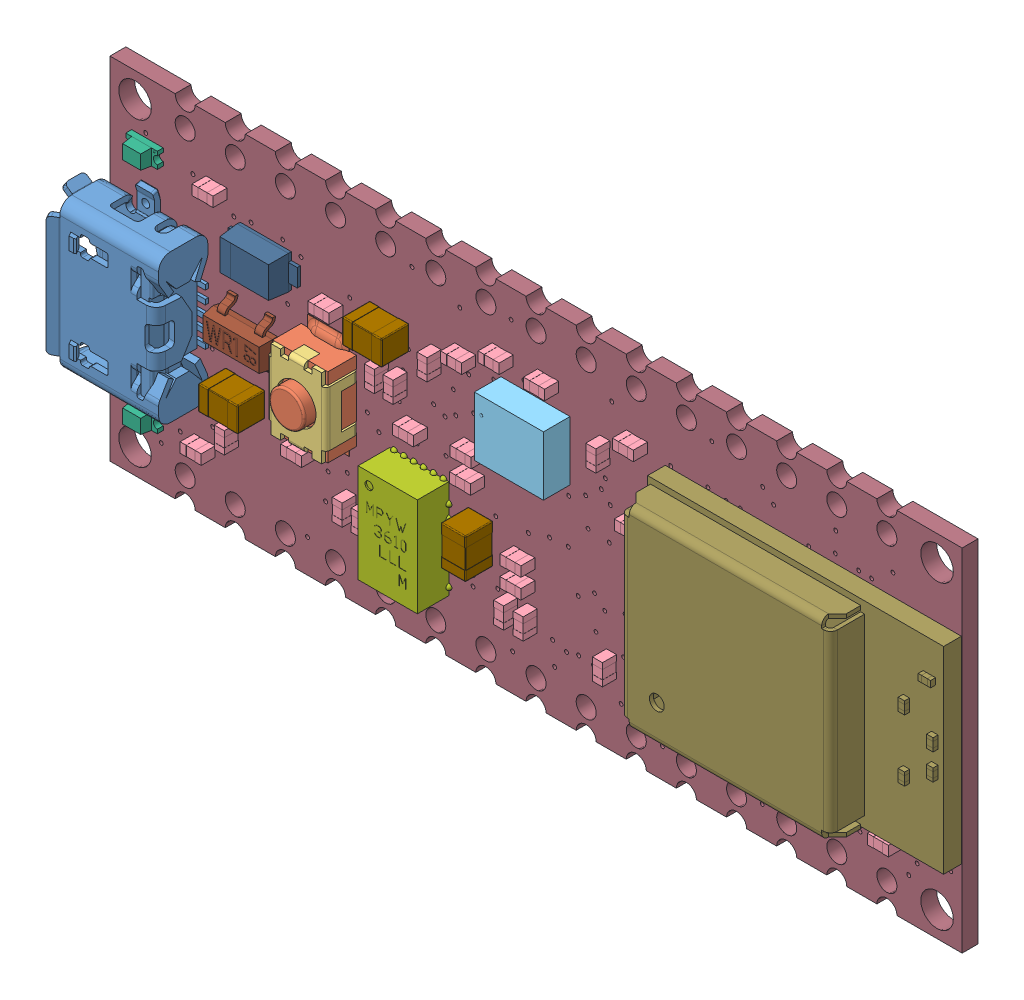
SolidWorks assembly Nano33BLE.step, configuration Default. Lengths in mm.
Overall size (43.8 17.78 3.58).
48 component instances, 13 part files, 0 mates.
Components (placement in the parent):
- NANO33BLE_V2.0 v1.step-1: NANO33BLE_V2.0 v1.step [Default] at origin size (43.8 17.78 3.58)
  - 3DComponents.step-1: 3DComponents.step [Default] at origin size (43.76 12.41 2.95)
    - zx62-ab-5pa_31_ v1.step-1: zx62-ab-5pa_31_ v1.step [Default] x (-1 0 0) z (0 1 0) size (5.6 2.95 8.8)
      - 6850961.step-1: 6850961.step [Default] at origin size (5.6 2.95 8.8)
        - ZX62-AB-5PA (1).step-1: ZX62-AB-5PA (1).step [Default] at (-4.98 1.125 5.465) size (5.6 2.95 8.8)
    - IoT_Reser Button v1.step-1: IoT_Reser Button v1.step [Default] x (0 -1 0) z (-1 0 0) size (5.2 2.15 3)
      - User Library-arduino_nano_reset core.step-1: User Library-arduino_nano_reset core.step [Default] at (-8.89 0.805 -11.09) size (5.2 2.15 2.8)
      - User Library-arduino_nano_reset shell.step-1: User Library-arduino_nano_reset shell.step [Default] at (-8.89 2.455 -11.09) x (0 0 1) z (-1 0 0) size (3 1.65 4)
    - RC0402FR-071KL.step-1: RC0402FR-071KL.step [Default] at origin size (35.89 12.12 0.71)
      - RC0402FR-071KL RC0402N_YAG v1.step-1: RC0402FR-071KL RC0402N_YAG v1.step [Default] at (4.8 3.0875 0.805) size (1.07 0.51 0.71)
      - RC0402FR-071KL RC0402N_YAG v1.step-2: RC0402FR-071KL RC0402N_YAG v1.step [Default] at (6.25 4.4075 0.805) x (0 -1 0) z (0 0 1) size (1.07 0.51 0.71)
      - RC0402FR-071KL RC0402N_YAG v1.step-3: RC0402FR-071KL RC0402N_YAG v1.step [Default] at (9.8875 5.5375 0.805) size (1.07 0.51 0.71)
      - RC0402FR-071KL RC0402N_YAG v1.step-4: RC0402FR-071KL RC0402N_YAG v1.step [Default] at (11.27 12.5 0.805) size (1.07 0.51 0.71)
      - RC0402FR-071KL RC0402N_YAG v1.step-5: RC0402FR-071KL RC0402N_YAG v1.step [Default] at (5.4 14.7 0.805) size (1.07 0.51 0.71)
      - RC0402FR-071KL RC0402N_YAG v1.step-6: RC0402FR-071KL RC0402N_YAG v1.step [Default] at (12.225 4.225 0.805) x (0 1 0) z (0 0 1) size (1.07 0.51 0.71)
      - RC0402FR-071KL RC0402N_YAG v1.step-7: RC0402FR-071KL RC0402N_YAG v1.step [Default] at (13.1875 4.2375 0.805) x (0 1 0) z (0 0 1) size (1.07 0.51 0.71)
      - RC0402FR-071KL RC0402N_YAG v1.step-8: RC0402FR-071KL RC0402N_YAG v1.step [Default] at (13.85 10.9 0.805) x (0 -1 0) z (0 0 1) size (1.07 0.51 0.71)
      - RC0402FR-071KL RC0402N_YAG v1.step-9: RC0402FR-071KL RC0402N_YAG v1.step [Default] at (14.8 10.9 0.805) x (0 -1 0) z (0 0 1) size (1.07 0.51 0.71)
      - RC0402FR-071KL RC0402N_YAG v1.step-10: RC0402FR-071KL RC0402N_YAG v1.step [Default] at (15.55 9.275 0.805) size (1.07 0.51 0.71)
      - RC0402FR-071KL RC0402N_YAG v1.step-11: RC0402FR-071KL RC0402N_YAG v1.step [Default] at (16.525 12.75 0.805) x (0 -1 0) z (0 0 1) size (1.07 0.51 0.71)
      - RC0402FR-071KL RC0402N_YAG v1.step-12: RC0402FR-071KL RC0402N_YAG v1.step [Default] at (18 13.675 0.805) size (1.07 0.51 0.71)
      - RC0402FR-071KL RC0402N_YAG v1.step-13: RC0402FR-071KL RC0402N_YAG v1.step [Default] at (18.475 9.775 0.805) size (1.07 0.51 0.71)
      - RC0402FR-071KL RC0402N_YAG v1.step-14: RC0402FR-071KL RC0402N_YAG v1.step [Default] at (18.45 8.6 0.805) size (1.07 0.51 0.71)
      - RC0402FR-071KL RC0402N_YAG v1.step-15: RC0402FR-071KL RC0402N_YAG v1.step [Default] at (21 6.275 0.805) size (1.07 0.51 0.71)
      - RC0402FR-071KL RC0402N_YAG v1.step-16: RC0402FR-071KL RC0402N_YAG v1.step [Default] at (21 5.275 0.805) size (1.07 0.51 0.71)
      - RC0402FR-071KL RC0402N_YAG v1.step-17: RC0402FR-071KL RC0402N_YAG v1.step [Default] at (20.405 3.8 0.805) x (0 -1 0) z (0 0 1) size (1.07 0.51 0.71)
      - RC0402FR-071KL RC0402N_YAG v1.step-18: RC0402FR-071KL RC0402N_YAG v1.step [Default] at (21.395 3.8126 0.805) x (0 -1 0) z (0 0 1) size (1.07 0.51 0.71)
      - RC0402FR-071KL RC0402N_YAG v1.step-19: RC0402FR-071KL RC0402N_YAG v1.step [Default] at (25.075 13.025 0.805) x (0 -1 0) z (0 0 1) size (1.07 0.51 0.71)
      - RC0402FR-071KL RC0402N_YAG v1.step-20: RC0402FR-071KL RC0402N_YAG v1.step [Default] at (26.7 14.2 0.805) size (1.07 0.51 0.71)
      - RC0402FR-071KL RC0402N_YAG v1.step-21: RC0402FR-071KL RC0402N_YAG v1.step [Default] at (39.625 3.32 0.805) size (1.07 0.51 0.71)
      - RC0402FR-071KL RC0402N_YAG v1.step-22: RC0402FR-071KL RC0402N_YAG v1.step [Default] at (37.675 3.32 0.805) size (1.07 0.51 0.71)
      - RC0402FR-071KL RC0402N_YAG v1.step-23: RC0402FR-071KL RC0402N_YAG v1.step [Default] at (35.7 3.3125 0.805) size (1.07 0.51 0.71)
      - RC0402FR-071KL RC0402N_YAG v1.step-24: RC0402FR-071KL RC0402N_YAG v1.step [Default] at (25.4125 3.8125 0.805) x (0 -1 0) z (0 0 1) size (1.07 0.51 0.71)
      - RC0402FR-071KL RC0402N_YAG v1.step-25: RC0402FR-071KL RC0402N_YAG v1.step [Default] at (26.8 10.7 0.805) size (1.07 0.51 0.71)
      - RC0402FR-071KL RC0402N_YAG v1.step-26: RC0402FR-071KL RC0402N_YAG v1.step [Default] at (19.9 14.625 0.805) size (1.07 0.51 0.71)
      - RC0402FR-071KL RC0402N_YAG v1.step-27: RC0402FR-071KL RC0402N_YAG v1.step [Default] at (22.2 14.625 0.805) size (1.07 0.51 0.71)
    - LSM9DS1TR_LGA-24_3X3P5X1_STM v1.step-1: LSM9DS1TR_LGA-24_3X3P5X1_STM v1.step [Default] at (21.5608 12.1142 0.754) size (3.5 3 1.4)
    - IoT_HSMG-C190 LED v1.step-1: IoT_HSMG-C190 LED v1.step [Default] at (1.9 3.1 0.805) x (1 0 0) z (0 -1 0) size (1.6 0.8 0.8)
    - IoT_MPM3610 Step-Down Module v1.step-1: IoT_MPM3610 Step-Down Module v1.step [Default] at (15.675 5.1865 1.605) x (-1 0 0) z (0 1 0) size (3.3 1.65 5.15)
    - IoT_HSMG-C190 LED v1.step-2: IoT_HSMG-C190 LED v1.step [Default] at (1.9 14.7 0.805) x (1 0 0) z (0 -1 0) size (1.6 0.8 0.8)
    - BLM18EG101TN1D v1.step-1: BLM18EG101TN1D v1.step [Default] at (33.0875 2.8875 1.2047) size (1.6 0.65 0.8)
    - C0805C472KDRACTU v1.step-1: C0805C472KDRACTU v1.step [Default] at (14.1625 13 0.8053) x (1 0 0) z (0 -1 0) size (2 1.4 1.25)
    - C0805C472KDRACTU v1.step-2: C0805C472KDRACTU v1.step [Default] at (18.7875 6.0875 0.8053) x (0 -1 0) z (-1 0 0) size (2 1.4 1.25)
    - PMEG6020AELRX v1.step-1: PMEG6020AELRX v1.step [Default] at (7.9 12.95 0.805) x (1 0 0) z (0 -1 0) size (3.5 1.1 1.7)
    - C0805C472KDRACTU v1.step-3: C0805C472KDRACTU v1.step [Default] at (6.8675 6.425 0.8053) x (1 0 0) z (0 -1 0) size (2 1.4 1.25)
    - IoT_PRTR5V0U2X Protection Diode v1.step-1: IoT_PRTR5V0U2X Protection Diode v1.step [Default] at (7.23 9.3 1.455) x (1 0 0) z (0 -1 0) size (3 1.1 2.5)
    - NINA-B306-00B-00--3DModel-STEP-56544 v1.step-1: NINA-B306-00B-00--3DModel-STEP-56544 v1.step [Default] at (35.642 8.89 0.805) x (0 1 0) z (1 0 0) size (10 2.63 15)
  - Board (1).step-1: Board (1).step [Default] at origin size (43.18 17.78 0.81)
